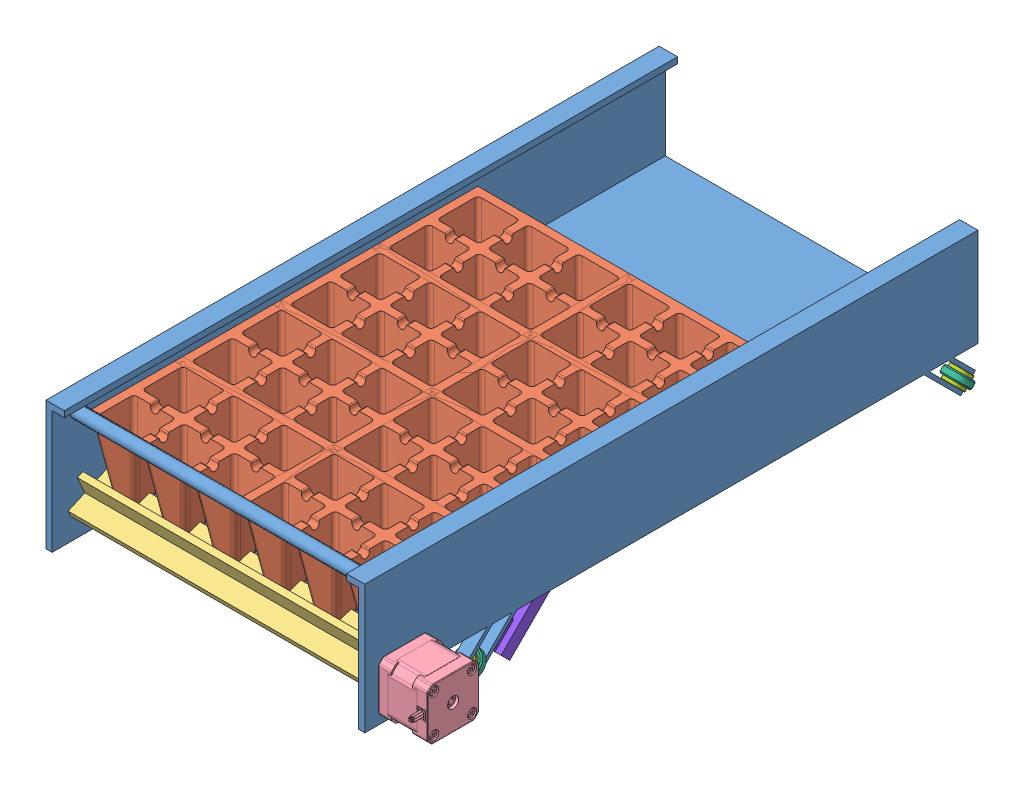
SolidWorks assembly tray_assembly, configuration Default. Lengths in mm.
Overall size (310.46 115.88 501.94).
22 component instances, 8 part files, 20 mates.
Components (placement in the parent):
- seedling_tray_holder-1: seedling_tray_holder [Default] at (362.2271 326.8382 246.3572) size (260 112.02 500)
- seed_tray_insert1-1: seed_tray_insert1 [Default] at (367.2271 386.8382 486.1542) x (-1 0 0) z (0 0 1) size (253.2 55 327.6)
- tray_mover-1: tray_mover [Default] at (237.2271 329.3382 716.3572) x (1 0 0) z (0 -0.407707 0.913113) size (250 35 35)
- nema  17-1: nema  17 [По умолчанию] at (534.2271 329.3382 716.3572) x (0 1 0) z (0 0 1) size (42.3 62 51.35)
- cheese head screw_as-1: cheese head screw_as [AS-NZS 1427 CH - M5 x 12-N] at (228.9271 329.3382 716.3572) size (15.32 8.5 8.5)
- v wheel-1: v wheel [Default] at (502.0975 292.5641 251.7186) x (0 0.707107 -0.707107) z (-0.213476 0.690807 0.690807) size (11 21.99 21.99)
  - v wheel outer cover-1: v wheel outer cover [Default] at (5.3844 11.4744 17.147) size (6 21 21)
  - W 625-2RS1-1: W 625-2RS1 [Default] at (5.8844 11.4744 17.147) x (1 0 0) z (0 0.854321 -0.519745) size (5 16 16)
  - W 625-2RS1-2: W 625-2RS1 [Default] at (-0.1156 11.4744 17.147) size (5 16 16)
- v wheel-3: v wheel [Default] at (252.7372 293.0565 252.2111) x (0 0.707107 -0.707107) z (-0.258016 0.683165 0.683165) size (11 21.99 21.99)
  - v wheel outer cover-1: v wheel outer cover [Default] at (5.3844 11.4744 17.147) size (6 21 21)
  - W 625-2RS1-1: W 625-2RS1 [Default] at (5.8844 11.4744 17.147) x (1 0 0) z (0 0.854321 -0.519745) size (5 16 16)
  - W 625-2RS1-2: W 625-2RS1 [Default] at (-0.1156 11.4744 17.147) size (5 16 16)
- v wheel-4: v wheel [Default] at (502.7372 310.1767 643.3831) x (0 0.707107 0.707107) z (-0.258016 -0.683165 0.683165) size (11 21.99 21.99)
  - v wheel outer cover-1: v wheel outer cover [Default] at (5.3844 11.4744 17.147) size (6 21 21)
  - W 625-2RS1-1: W 625-2RS1 [Default] at (5.8844 11.4744 17.147) x (1 0 0) z (0 0.854321 -0.519745) size (5 16 16)
  - W 625-2RS1-2: W 625-2RS1 [Default] at (-0.1156 11.4744 17.147) size (5 16 16)
- v wheel-5: v wheel [Default] at (252.7372 310.1767 643.3831) x (0 0.707107 0.707107) z (-0.258016 -0.683165 0.683165) size (11 21.99 21.99)
  - v wheel outer cover-1: v wheel outer cover [Default] at (5.3844 11.4744 17.147) size (6 21 21)
  - W 625-2RS1-1: W 625-2RS1 [Default] at (5.8844 11.4744 17.147) x (1 0 0) z (0 0.854321 -0.519745) size (5 16 16)
  - W 625-2RS1-2: W 625-2RS1 [Default] at (-0.1156 11.4744 17.147) size (5 16 16)
- geneva_slider2-1: geneva_slider2 [Default] at (484.7271 298.5539 632.7542) x (-1 0 0) z (0 -0.707107 0.707107) size (255 10 50)
Mates (geometry in assembly coordinates):
- Concentric1: concentric aligned: circle of tray_mover-1; cylinder of nema  17-1 through (472.2271 329.3382 716.3572) axis (1 0 0) radius 2.5
- Coincident2: coincident anti-aligned: plane of seedling_tray_holder-1 through (487.2271 401.8382 746.3572) normal (-1 0 0); plane of tray_mover-1 through (487.2271 329.3382 716.3572) normal (1 0 0)
- Coincident3: coincident anti-aligned: plane of seedling_tray_holder-1 through (492.2271 326.8382 746.3572) normal (1 0 0); plane of nema  17-1 through (492.2271 329.3382 716.3572) normal (-1 0 0)
- Coincident5: coincident anti-aligned: plane of seedling_tray_holder-1 through (487.2271 331.8382 746.3572) normal (0 1 0); plane of seed_tray_insert1-1 through (324.2271 331.8382 721.7542) normal (0 -1 0)
- Coincident6: coincident anti-aligned: plane of seedling_tray_holder-1 through (237.2271 401.8382 746.3572) normal (1 0 0); plane of seed_tray_insert1-1 through (237.2271 385.8382 726.7542) normal (-1 0 0)
- Concentric2: concentric anti-aligned: cylinder of seedling_tray_holder-1 through (492.2271 329.3382 716.3572) axis (-1 0 0) radius 2.5; cylinder of nema  17-1 through (472.2271 329.3382 716.3572) axis (1 0 0) radius 2.5
- Concentric3: concentric aligned: cylinder of seedling_tray_holder-1 through (492.2271 329.3382 716.3572) axis (-1 0 0) radius 2.5; cylinder of cheese head screw_as-1 through (228.9271 329.3382 716.3572) axis (-1 0 0) radius 2.5
- Coincident8: coincident anti-aligned: plane of seedling_tray_holder-1 through (232.2271 326.8382 746.3572) normal (-1 0 0); plane of cheese head screw_as-1 through (232.2271 333.5882 716.3572) normal (1 0 0)
- Parallel1: parallel aligned: plane of seedling_tray_holder-1 through (362.2271 326.8382 746.3572) normal (0 0 1); plane of nema  17-1 through (502.2271 314.9147 737.5072) normal (0 0 1)
- Concentric4: concentric anti-aligned: cylinder of seedling_tray_holder-1 through (487.2271 317.4951 247.014) axis (0 -0.707107 0.707107) radius 2.5; cylinder of v wheel-1/W 625-2RS1-1 through (487.2271 342.1936 222.3156) axis (0 0.707107 -0.707107) radius 2.4998
- Coincident9: coincident anti-aligned: plane of seedling_tray_holder-1 through (482.2271 306.8382 250.5998) normal (0 -0.707107 0.707107); plane of v wheel-1/W 625-2RS1-1 through (489.1594 308.941 252.7026) normal (0 0.707107 -0.707107)
- Concentric5: concentric anti-aligned: cylinder of seedling_tray_holder-1 through (237.2271 317.4951 247.014) axis (0 -0.707107 0.707107) radius 2.5; cylinder of v wheel-3/W 625-2RS1-1 through (237.2271 342.1936 222.3156) axis (0 0.707107 -0.707107) radius 2.4998
- Coincident10: coincident anti-aligned: plane of seedling_tray_holder-1 through (242.2271 306.8382 250.5998) normal (0 -0.707107 0.707107); plane of v wheel-3/W 625-2RS1-1 through (239.2502 309.0051 252.7667) normal (0 0.707107 -0.707107)
- Concentric6: concentric anti-aligned: cylinder of seedling_tray_holder-1 through (487.2271 315.3737 667.8217) axis (0 -0.707107 -0.707107) radius 2.5; cylinder of v wheel-4/W 625-2RS1-2 through (487.2271 335.8296 688.2775) axis (0 0.707107 0.707107) radius 2.4998
- Coincident11: coincident anti-aligned: plane of seedling_tray_holder-1 through (482.2271 326.8382 642.1145) normal (0 -0.707107 -0.707107); plane of v wheel-4/W 625-2RS1-1 through (489.2502 309.621 659.3317) normal (0 0.707107 0.707107)
- Concentric7: concentric anti-aligned: cylinder of seedling_tray_holder-1 through (237.2271 315.3737 667.8217) axis (0 -0.707107 -0.707107) radius 2.5; cylinder of v wheel-5/W 625-2RS1-2 through (237.2271 335.8296 688.2775) axis (0 0.707107 0.707107) radius 2.4998
- Coincident12: coincident anti-aligned: plane of seedling_tray_holder-1 through (242.2271 326.8382 642.1145) normal (0 -0.707107 -0.707107); plane of v wheel-5/W 625-2RS1-1 through (239.2502 309.621 659.3317) normal (0 0.707107 0.707107)
- Angle2: planar angle = 2.356194 rad aligned: plane of geneva_slider2-1 through (489.7271 326.8382 590.3278) normal (0 0.707107 -0.707107); plane of seedling_tray_holder-1 through (232.2271 326.8382 746.3572) normal (0 -1 0)
- Coincident15: coincident: plane of seedling_tray_holder-1 through (232.2271 326.8382 746.3572) normal (0 -1 0); line of geneva_slider2-1 through (234.7271 326.8382 590.3278) axis (1 0 0)
- Distance2: distance = 2.5 mm aligned: plane of seedling_tray_holder-1 through (232.2271 326.8382 746.3572) normal (-1 0 0); plane of geneva_slider2-1 through (234.7271 312.6961 604.4699) normal (-1 0 0)
